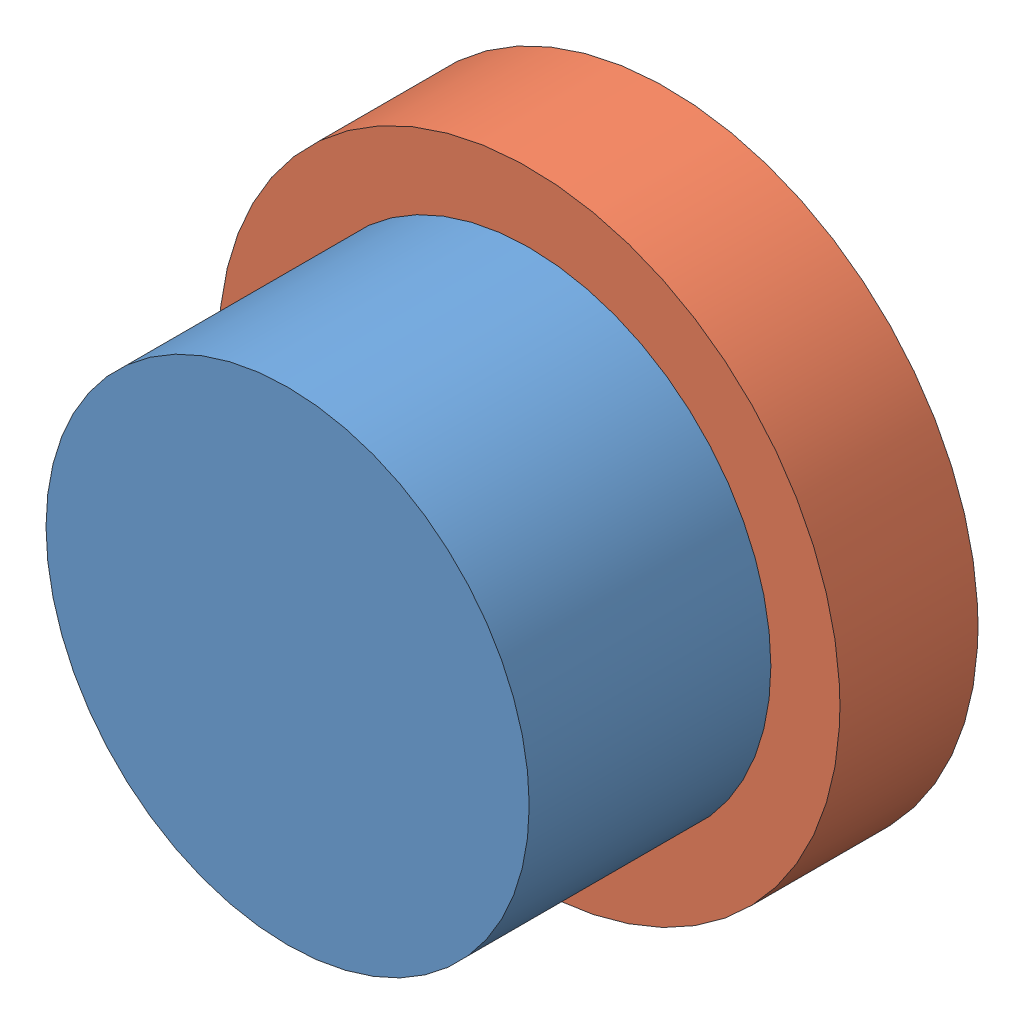
SolidWorks assembly Assem2, configuration Default. Lengths in mm.
Overall size (22.86 22.86 13.97).
2 component instances, 2 part files, 2 mates.
Components (placement in the parent):
- green-1: green [Default] at (24.2529 17.9955 3.2773) size (17.78 17.78 8.89)
- Holder-1: Holder [Default] at (24.2529 17.9955 -1.8027) size (22.86 22.86 5.08)
Mates (geometry in assembly coordinates):
- Coincident1: coincident: plane of green-1 through (24.2529 17.9955 3.2773) normal (0 0 -1); plane of Holder-1 through (24.2529 17.9955 3.2773) normal (0 0 1)
- Concentric1: concentric aligned: circle of green-1; circle of Holder-1
